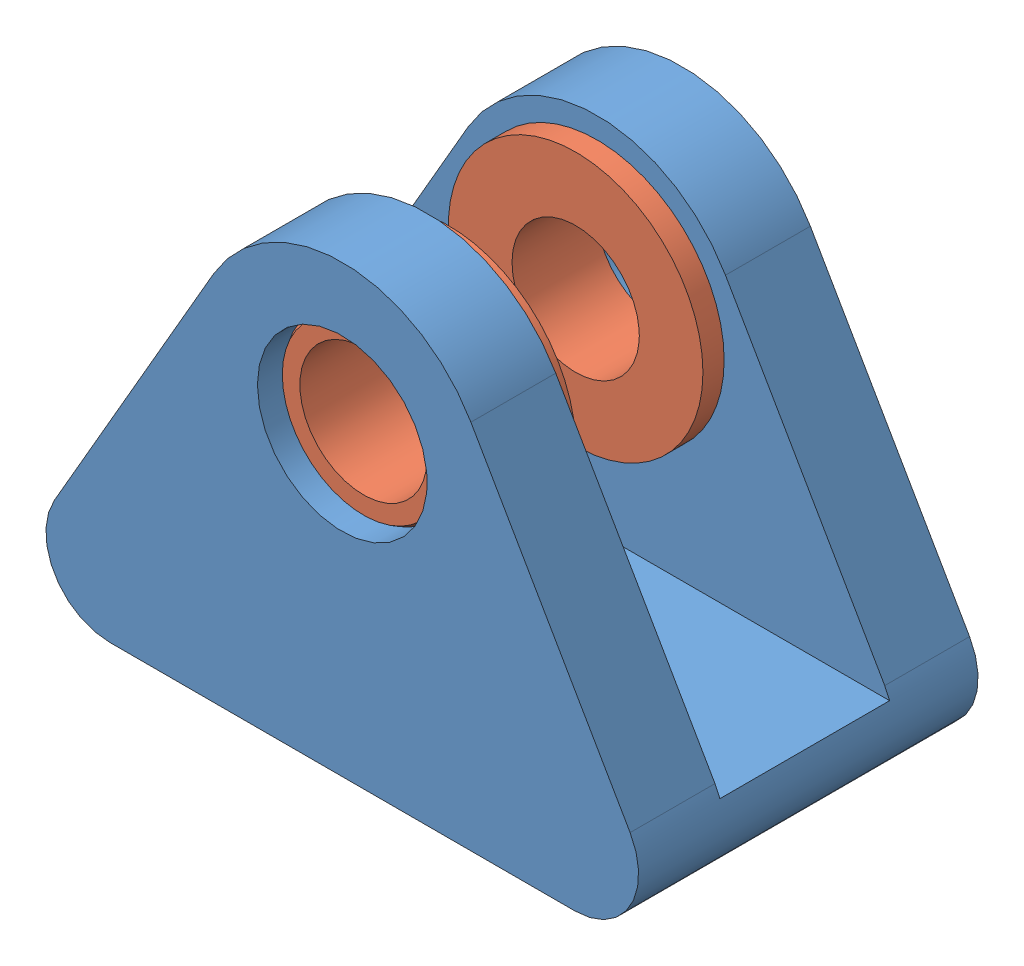
SolidWorks assembly Cubli2D, configuration Default. Lengths in mm.
Overall size (27.94 21 16).
3 component instances, 2 part files, 6 mates.
Components (placement in the parent):
- Pivot-1: Pivot [Default] at origin size (27.94 21 16)
- FlangedBushing-1: FlangedBushing [Default] at (0 0 -11) size (12 12 4)
- FlangedBushing-2: FlangedBushing [Default] at (0 0 3) x (-1 0 0) z (0 0 -1) size (12 12 4)
Mates (geometry in assembly coordinates):
- Concentric1: concentric anti-aligned: cylinder of Pivot-1 through (0 0 -12) axis (0 0 1) radius 4; cylinder of FlangedBushing-1 through (0 0 -7) axis (0 0 -1) radius 4
- Coincident1: coincident anti-aligned: plane of Pivot-1 through (0 0 -8) normal (0 0 1); plane of FlangedBushing-1 through (0 0 -8) normal (0 0 -1)
- Parallel1: parallel aligned: plane of Pivot-1 through (0 0 0) normal (1 0 0); plane of FlangedBushing-1 through (0 0 -11) normal (1 0 0)
- Concentric2: concentric anti-aligned: cylinder of Pivot-1 through (0 0 4) axis (0 0 -1) radius 4; cylinder of FlangedBushing-2 through (0 0 -1) axis (0 0 1) radius 4
- Coincident2: coincident anti-aligned: plane of Pivot-1 through (0 0 0) normal (0 0 -1); plane of FlangedBushing-2 through (0 0 0) normal (0 0 1)
- Parallel2: parallel anti-aligned: plane of Pivot-1 through (0 0 0) normal (1 0 0); plane of FlangedBushing-2 through (0 0 3) normal (-1 0 0)
